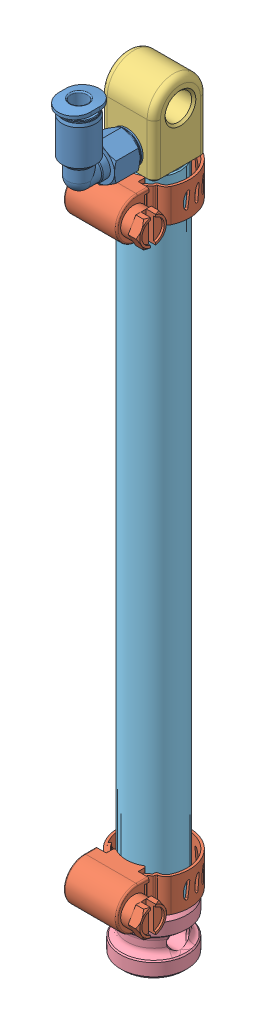
SolidWorks assembly AARL_QR_RL_MA_FA, configuration Default. Lengths in mm.
Overall size (19.43 185.56 31.28).
6 component instances, 5 part files, 15 mates.
Components (placement in the parent):
- AARL_Puppy_18_02_57_010-QSML-M3-4-1: AARL_Puppy_18_02_57_010-QSML-M3-4 [Default] at (-100.6607 79.2597 19.2077) x (0 1 0) z (0 0 -1) size (20.32 8 18.9)
- AARL_Puppy_18_02_57_011-5388K140_Hose-Clamp-1: AARL_Puppy_18_02_57_011-5388K140_Hose-Clamp [5388K14] at (-100.6607 69.5442 1.3577) x (1 0 0) z (0 -1 0) size (19.43 23.71 9.91)
- AARL_Puppy_18_02_57_011-5388K140_Hose-Clamp-2: AARL_Puppy_18_02_57_011-5388K140_Hose-Clamp [5388K14] at (-100.6607 -72.9498 1.3577) x (1 0 0) z (0 -1 0) size (19.43 23.71 9.91)
- AARL_QR_PN_EP_001-1: AARL_QR_PN_EP_001 [Default] at (-100.6607 87.1972 1.3577) x (0 0 1) z (-1 0 0) size (12.7 31.75 12.7)
- AARL_QR_PN_EP_002-1: AARL_QR_PN_EP_002 [Default] at (-100.6607 -77.9028 1.3577) x (-1 0 0) z (0 0 1) size (15.88 25.4 15.88)
- BPA main body 6INin-1: BPA main body 6INin [Resting] at (-100.6607 -1.7028 1.3577) size (12.7 152.4 12.7)
Mates (geometry in assembly coordinates):
- Parallel1: parallel aligned: plane of AARL_QR_PN_EP_001-1 through (-107.0107 74.4972 7.7077) normal (0 0 1)
- Concentric2: concentric aligned: cylinder of AARL_Puppy_18_02_57_010-QSML-M3-4-1 through (-100.6607 79.2597 7.7077) axis (0 0 1) radius 1.5; cylinder of AARL_QR_PN_EP_001-1 through (-100.6607 79.2597 7.7077) axis (0 0 1) radius 2.0193
- Perpendicular1: perpendicular: plane of AARL_Puppy_18_02_57_010-QSML-M3-4-1 through (-104.6607 76.9502 14.7633) normal (-1 0 0); plane of AARL_QR_PN_EP_001-1 through (-107.0107 74.4972 -4.9923) normal (0 -1 0)
- Coincident4: coincident anti-aligned: plane of AARL_Puppy_18_02_57_010-QSML-M3-4-1 through (-100.6607 79.2597 7.7077) normal (0 0 -1); plane of AARL_QR_PN_EP_001-1 through (-107.0107 74.4972 7.7077) normal (0 0 1)
- Coincident5: coincident aligned: plane of AARL_Puppy_18_02_57_011-5388K140_Hose-Clamp-1 through (-94.3107 69.5442 11.5914) normal (1 0 0); plane of AARL_QR_PN_EP_001-1 through (-94.3107 87.1972 1.3577) normal (1 0 0)
- Coincident6: coincident anti-aligned: plane of AARL_Puppy_18_02_57_011-5388K140_Hose-Clamp-1 through (-100.6607 74.4972 1.3577) normal (0 1 0); plane of AARL_QR_PN_EP_001-1 through (-107.0107 74.4972 -4.9923) normal (0 -1 0)
- Parallel3: parallel anti-aligned: cylinder of AARL_QR_PN_EP_001-1 through (-107.0107 87.1972 1.3577) axis (1 0 0) radius 3.175; cylinder of AARL_QR_PN_EP_002-1 through (-92.7232 -84.2528 1.3577) axis (-1 0 0) radius 2.3813
- Coincident8: coincident aligned: plane of AARL_Puppy_18_02_57_011-5388K140_Hose-Clamp-1 through (-94.3107 69.5442 11.5914) normal (1 0 0); plane of AARL_Puppy_18_02_57_011-5388K140_Hose-Clamp-2 through (-94.3107 -72.9498 11.5914) normal (1 0 0)
- Coincident9: coincident anti-aligned: plane of AARL_Puppy_18_02_57_011-5388K140_Hose-Clamp-2 through (-100.6607 -77.9028 1.3577) normal (0 -1 0); plane of AARL_QR_PN_EP_002-1 through (-105.0263 -77.9028 1.3577) normal (0 1 0)
- Concentric3: concentric anti-aligned: circle of AARL_QR_PN_EP_001-1; cylinder of BPA main body 6INin-1 through (-100.6607 9.9057 1.3577) axis (0 1 0) radius 6.35
- Concentric4: concentric aligned: cylinder of AARL_Puppy_18_02_57_011-5388K140_Hose-Clamp-1 through (-100.6607 65.5754 1.3577) axis (0 1 0) radius 8.5217; cylinder of BPA main body 6INin-1 through (-100.6607 9.9057 1.3577) axis (0 1 0) radius 6.35
- Concentric5: concentric aligned: cylinder of AARL_Puppy_18_02_57_011-5388K140_Hose-Clamp-2 through (-100.6607 -76.9186 1.3577) axis (0 1 0) radius 8.5217; cylinder of BPA main body 6INin-1 through (-100.6607 9.9057 1.3577) axis (0 1 0) radius 6.35
- Concentric6: concentric aligned: circle of AARL_QR_PN_EP_002-1; cylinder of BPA main body 6INin-1 through (-100.6607 9.9057 1.3577) axis (0 1 0) radius 6.35
- Coincident10: coincident anti-aligned: plane of AARL_QR_PN_EP_001-1 through (-107.0107 74.4972 -4.9923) normal (0 -1 0); plane of BPA main body 6INin-1 through (-95.8982 74.4972 1.3577) normal (0 1 0)
- Coincident11: coincident anti-aligned: plane of AARL_QR_PN_EP_002-1 through (-105.0263 -77.9028 1.3577) normal (0 1 0); plane of BPA main body 6INin-1 through (-94.3107 -77.9028 1.3577) normal (0 -1 0)
